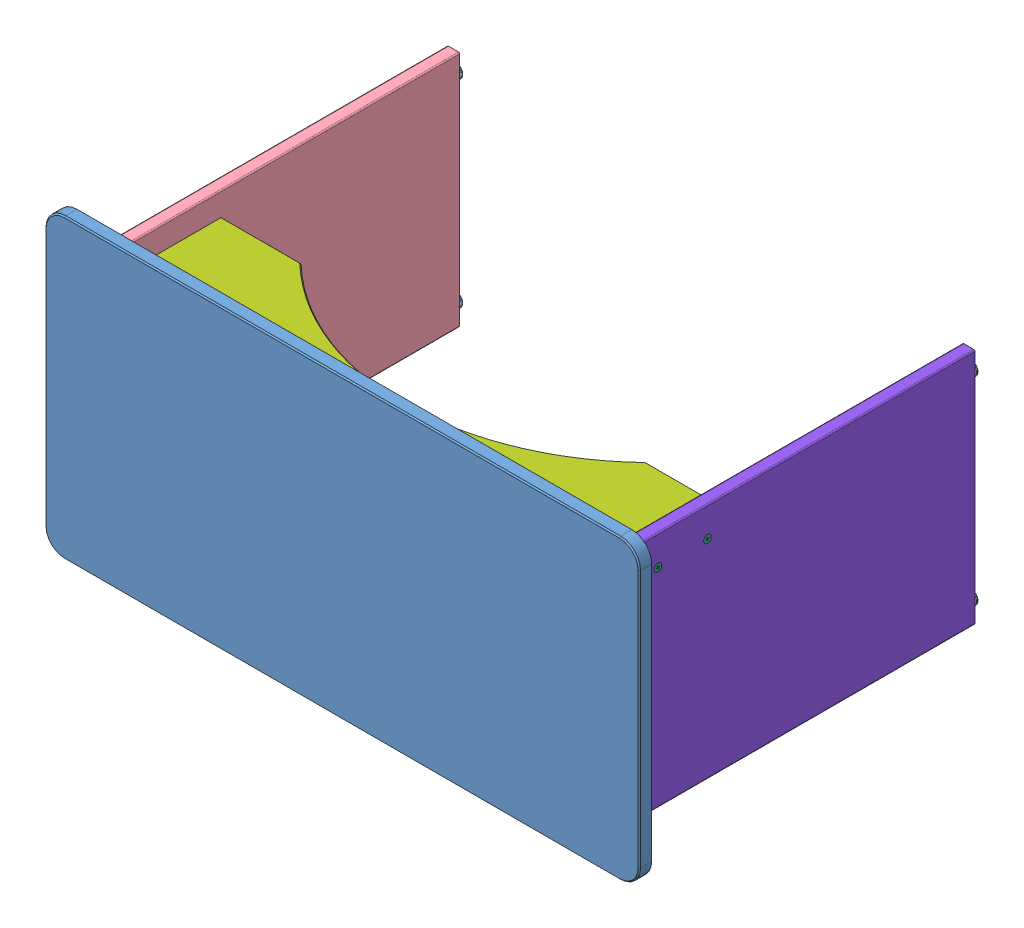
SolidWorks assembly E20, configuration Default. Lengths in mm.
Overall size (1524 762 953.14).
20 component instances, 8 part files, 25 mates.
Components (placement in the parent):
- Desk Top-1: Desk Top [Default] at (463.0401 791.5052 1228.2271) size (1524 762 31.75)
- Dowel-1: Dowel [Default] at (1123.4401 512.1052 1218.7021) size (9.53 9.53 38.1)
- Dowel-2: Dowel [Default] at (1123.4401 1070.9052 1218.7021) size (9.53 9.53 38.1)
- Dowel-3: Dowel [Default] at (-197.3599 512.1052 1218.7021) size (9.53 9.53 38.1)
- Dowel-4: Dowel [Default] at (-197.3599 1070.9052 1218.7021) size (9.53 9.53 38.1)
- Fastening Bolt-1: Fastening Bolt [Default] at (1123.4401 613.7052 1237.7521) x (-0.601294 -0.799028 0) z (0 0 -1) size (13.45 13.45 50.8)
- Fastening Bolt-2: Fastening Bolt [Default] at (1123.4401 969.3052 1237.7521) x (-0.69621 -0.717838 0) z (0 0 -1) size (13.45 13.45 50.8)
- Fastening Bolt-3: Fastening Bolt [Default] at (-197.3599 613.7052 1237.7521) x (-0.601294 0.799028 0) z (0 0 -1) size (13.45 13.45 50.8)
- Fastening Bolt-4: Fastening Bolt [Default] at (-197.3599 969.3052 1237.7521) x (-0.69621 0.717838 0) z (0 0 -1) size (13.45 13.45 50.8)
- Leg-1: Leg [Default] at (463.0401 791.5052 1228.2271) x (1 0 0) z (0 -1 0) size (31.75 914.4 609.6)
- Caster-1: Caster [Default] at (-197.3599 1045.5052 290.9671) x (0.856224 -0.516604 0) z (-0.516604 -0.856224 0) size (34.92 38.1 34.92)
- Caster-4: Caster [Default] at (-197.3599 537.5052 290.9671) x (-0.940784 -0.339006 0) z (-0.339006 0.940784 0) size (34.92 38.1 34.92)
- Bolt-1: Bolt [Default] at (-207.3929 1020.1052 983.7521) x (0 0.933332 0.359015) z (1 0 0) size (19.69 19.69 56.64)
- Bolt-2: Bolt [Default] at (-207.3929 1020.1052 1110.7521) x (0 0.386899 -0.922122) z (1 0 0) size (19.69 19.69 56.64)
- Rib-1: Rib [Default] at (463.0401 791.5052 1228.2271) x (0 1 0) z (1 0 0) size (31.75 304.8 1289.05)
- Caster-5: Caster [Default] at (1123.4401 1045.5052 290.9671) x (-0.856224 -0.516604 0) z (-0.516604 0.856224 0) size (34.92 38.1 34.92)
- Caster-6: Caster [Default] at (1123.4401 537.5052 290.9671) x (0.940784 -0.339006 0) z (-0.339006 -0.940784 0) size (34.92 38.1 34.92)
- Bolt-3: Bolt [Default] at (1133.4731 1020.1052 983.7521) x (0 -0.933332 -0.359015) z (-1 0 0) size (19.69 19.69 56.64)
- Bolt-4: Bolt [Default] at (1133.4731 1020.1052 1110.7521) x (0 -0.386899 0.922122) z (-1 0 0) size (19.69 19.69 56.64)
- MirrorLeg-2: MirrorLeg [Default] at (463.0401 791.5052 1228.2271) x (-1 0 0) z (0 1 0) size (31.75 914.4 609.6)
Mates (geometry in assembly coordinates):
- Concentric11: concentric aligned: cylinder of Desk Top-1 through (1123.4401 512.1052 1212.3521) axis (0 0 -1) radius 4.7625; cylinder of Dowel-1 through (1123.4401 512.1052 1237.7521) axis (0 0 -1) radius 4.7625
- Concentric21: concentric aligned: cylinder of Desk Top-1 through (1123.4401 1070.9052 1212.3521) axis (0 0 -1) radius 4.7625; cylinder of Dowel-2 through (1123.4401 1070.9052 1237.7521) axis (0 0 -1) radius 4.7625
- Concentric31: concentric aligned: cylinder of Desk Top-1 through (-197.3599 512.1052 1212.3521) axis (0 0 -1) radius 4.7625; cylinder of Dowel-3 through (-197.3599 512.1052 1237.7521) axis (0 0 -1) radius 4.7625
- Concentric41: concentric aligned: cylinder of Desk Top-1 through (-197.3599 1070.9052 1212.3521) axis (0 0 -1) radius 4.7625; cylinder of Dowel-4 through (-197.3599 1070.9052 1237.7521) axis (0 0 -1) radius 4.7625
- Distance1: distance = 12.7 mm aligned: plane of Dowel-1 through (1123.4401 512.1052 1199.6521) normal (0 0 -1); plane of Desk Top-1 through (-298.9599 1172.5052 1212.3521) normal (0 0 -1)
- Coincident1: coincident aligned: plane of Dowel-1 through (1123.4401 512.1052 1199.6521) normal (0 0 -1); plane of Dowel-2 through (1123.4401 1070.9052 1199.6521) normal (0 0 -1)
- Coincident2: coincident aligned: plane of Dowel-1 through (1123.4401 512.1052 1199.6521) normal (0 0 -1); plane of Dowel-3 through (-197.3599 512.1052 1199.6521) normal (0 0 -1)
- Coincident4: coincident aligned: plane of Dowel-1 through (1123.4401 512.1052 1199.6521) normal (0 0 -1); plane of Dowel-4 through (-197.3599 1070.9052 1199.6521) normal (0 0 -1)
- Concentric51: concentric anti-aligned: cylinder of Desk Top-1 through (1123.4401 613.7052 1212.3521) axis (0 0 -1) radius 4.7625; cylinder of Fastening Bolt-1 through (1123.4401 613.7052 1212.3521) axis (0 0 1) radius 4.7625
- Coincident5: coincident aligned: plane of Desk Top-1 through (-298.9599 1172.5052 1212.3521) normal (0 0 -1); plane of Fastening Bolt-1 through (1123.4401 613.7052 1212.3521) normal (0 0 -1)
- Concentric61: concentric anti-aligned: cylinder of Desk Top-1 through (1123.4401 969.3052 1212.3521) axis (0 0 -1) radius 4.7625; cylinder of Fastening Bolt-2 through (1123.4401 969.3052 1212.3521) axis (0 0 1) radius 4.7625
- Coincident6: coincident aligned: plane of Desk Top-1 through (-298.9599 1172.5052 1212.3521) normal (0 0 -1); plane of Fastening Bolt-2 through (1123.4401 969.3052 1212.3521) normal (0 0 -1)
- Coincident7: coincident anti-aligned: plane of Desk Top-1 through (-298.9599 1172.5052 1212.3521) normal (0 0 -1); plane of Leg-1 through (-181.4849 486.7052 1212.3521) normal (0 0 1)
- Concentric7: concentric aligned: cylinder of Fastening Bolt-4 through (-197.3599 969.3052 1190.1271) axis (0 0 1) radius 2.54; cylinder of Leg-1 through (-197.3599 969.3052 1186.9521) axis (0 0 1) radius 4.7625
- Concentric8: concentric aligned: cylinder of Fastening Bolt-3 through (-197.3599 613.7052 1190.1271) axis (0 0 1) radius 2.54; cylinder of Leg-1 through (-197.3599 613.7052 1186.9521) axis (0 0 1) radius 4.7625
- Concentric91: concentric aligned: cylinder of Leg-1 through (-197.3599 1045.5052 297.9521) axis (0 0 -1) radius 4.7625; cylinder of Caster-1 through (-197.3599 1045.5052 290.9671) axis (0 0 -1) radius 4.7625
- Coincident8: coincident anti-aligned: plane of Leg-1 through (-213.2349 486.7052 297.9521) normal (0 0 -1); circle of Caster-4
- Concentric11: concentric aligned: cylinder of Leg-1 through (-197.3599 537.5052 297.9521) axis (0 0 -1) radius 4.7625; cylinder of Caster-4 through (-197.3599 537.5052 290.9671) axis (0 0 -1) radius 4.7625
- Coincident9: coincident anti-aligned: plane of Leg-1 through (-213.2349 486.7052 297.9521) normal (0 0 -1); circle of Caster-1
- Coincident10: coincident aligned: plane of Leg-1 through (-213.2349 486.7052 1212.3521) normal (-1 0 0); plane of Bolt-2 through (-213.2349 1020.1052 1110.7521) normal (-1 0 0)
- Concentric13: concentric aligned: cylinder of Leg-1 through (-213.2349 1020.1052 1110.7521) axis (-1 0 0) radius 5.0419; cylinder of Bolt-2 through (-156.5929 1020.1052 1110.7521) axis (-1 0 0) radius 4.7625
- Concentric14: concentric aligned: cylinder of Leg-1 through (-213.2349 1020.1052 983.7521) axis (-1 0 0) radius 5.0419; cylinder of Bolt-1 through (-156.5929 1020.1052 983.7521) axis (-1 0 0) radius 4.7625
- Coincident11: coincident aligned: plane of Leg-1 through (-213.2349 486.7052 1212.3521) normal (-1 0 0); plane of Bolt-1 through (-213.2349 1020.1052 983.7521) normal (-1 0 0)
- Coincident12: coincident aligned: circle of Leg-1; circle of Rib-1
- Concentric15: concentric aligned: line of Bolt-1 through (-159.1329 1020.1052 983.7521) axis (-1 0 0); cylinder of Rib-1 through (-156.0849 1020.1052 983.7521) axis (-1 0 0) radius 5.0419
